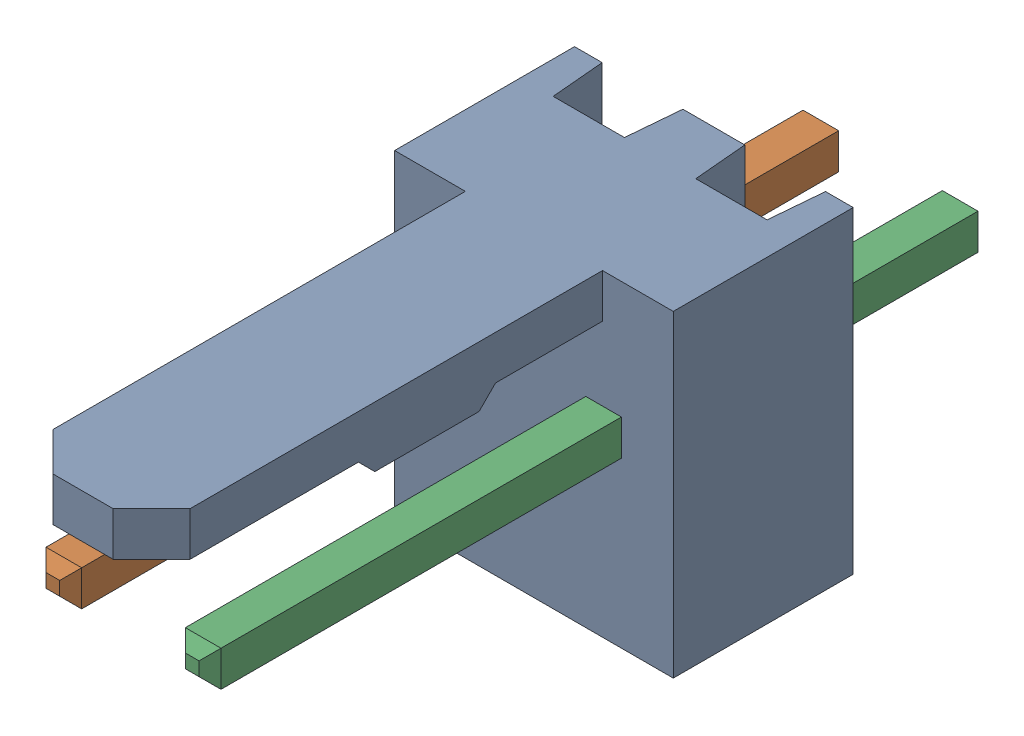
SolidWorks assembly Molex PCB 2 pin v2, configuration Default. Lengths in mm.
Overall size (5.08 5.79 14.92).
3 component instances, 2 part files, 0 mates.
Components (placement in the parent):
- BASE9710016_1-1: BASE9710016_1 [Default] at (2.54 2.895 -8.22) size (5.08 5.79 11.5)
- PINO9710016_1-1: PINO9710016_1 [Default] at (1.27 3.325 -0.72) size (0.65 0.65 14.2)
- PINO9710016_1-2: PINO9710016_1 [Default] at (3.81 3.325 -0.72) size (0.65 0.65 14.2)
